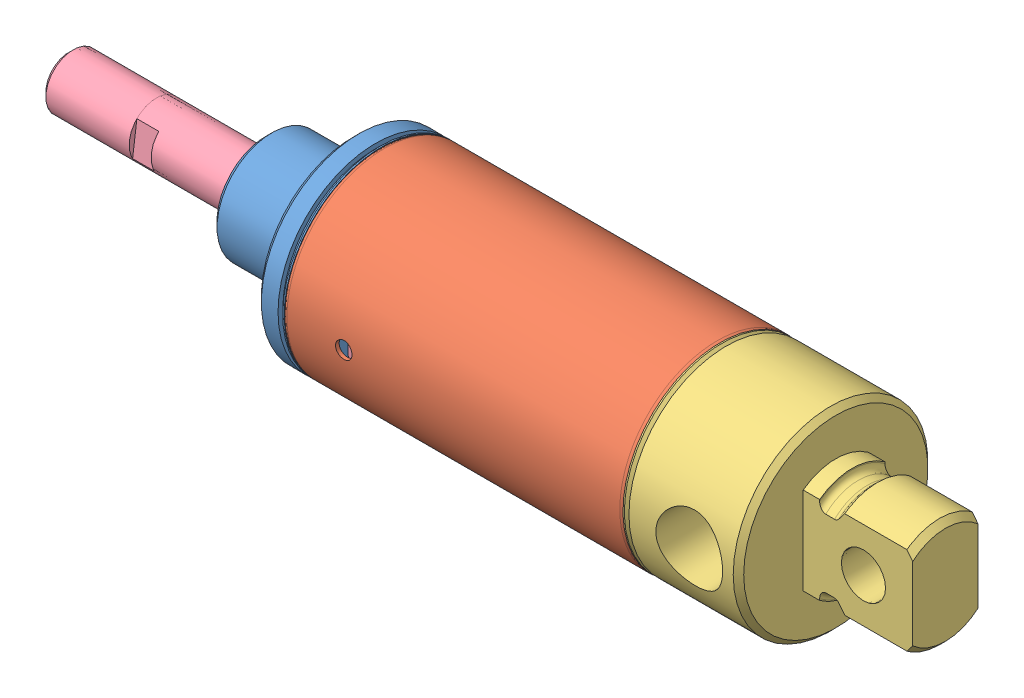
SolidWorks assembly 090_5-P, configuration Default. Lengths in mm.
Overall size (127.03 30.42 30.42).
5 component instances, 5 part files, 11 mates.
Components (placement in the parent):
- 090_5-PC0000_0_dummy-1: 090_5-PC0000_0_dummy [Default] at origin
- 09000-0_rod_guide-1: 09000-0_rod_guide [Default] at origin size (25.4 28.27 28.27)
- 09-1_9412C-1: 09-1_9412C [Default] at (16.637 0 0) size (50.65 28.27 28.27)
- 09P0000_rear_head-1: 09P0000_rear_head [Default] at (60.3504 0 0) size (38.1 28.22 28.22)
- C-090_5-P0_rod-1: C-090_5-P0_rod [Default] at (-12.7 0 0) x (1 0 0) z (0 0.130321 0.991472) size (76.23 27.11 27.11)
Mates (geometry in assembly coordinates):
- Distance2: distance = 0 mm aligned: plane of 09000-0_rod_guide-1 through (0 0 0) normal (1 0 0); plane of 090_5-PC0000_0_dummy-1 through (0 0 0) normal (1 0 0)
- Coincident1: coincident aligned: line of 090_5-PC0000_0_dummy-1 through (80.9 0 0) axis (-1 0 0); line of 09000-0_rod_guide-1 through (80.9 0 0) axis (-1 0 0)
- Angle3: planar angle = 0 rad aligned: plane of 09000-0_rod_guide-1 through (0 0 0) normal (0 0 -1); plane of 090_5-PC0000_0_dummy-1 through (0 0 0) normal (0 0 -1)
- Distance4: distance = 0 mm aligned: plane of 09-1_9412C-1 through (16.637 0 0) normal (1 0 0); plane of 09000-0_rod_guide-1 through (16.637 0 0) normal (1 0 0)
- Coincident2: coincident aligned: line of 09000-0_rod_guide-1 through (80.9 0 0) axis (-1 0 0); line of 09-1_9412C-1 through (97.537 0 0) axis (-1 0 0)
- Angle6: planar angle = 0 rad aligned: plane of 09-1_9412C-1 through (16.637 0 0) normal (0 0 -1); plane of 09000-0_rod_guide-1 through (0 0 0) normal (0 0 -1)
- Distance6: distance = 0 mm aligned: plane of 09P0000_rear_head-1 through (65.9384 0 0) normal (1 0 0); plane of 09-1_9412C-1 through (65.9384 0 0) normal (1 0 0)
- Coincident3: coincident aligned: line of 09-1_9412C-1 through (97.537 0 0) axis (-1 0 0); line of 09P0000_rear_head-1 through (141.2504 0 0) axis (-1 0 0)
- Angle9: planar angle = 0 rad aligned: plane of 09P0000_rear_head-1 through (60.3504 0 0) normal (0 0 -1); plane of 09-1_9412C-1 through (16.637 0 0) normal (0 0 -1)
- LimitDistance2: limit distance = 12.7 mm aligned: plane of C-090_5-P0_rod-1; plane of 09000-0_rod_guide-1 through (0 0 0) normal (1 0 0)
- Coincident5: coincident aligned: line of 09000-0_rod_guide-1 through (80.9 0 0) axis (-1 0 0); line of C-090_5-P0_rod-1 through (68.2 0 0) axis (-1 0 0)
